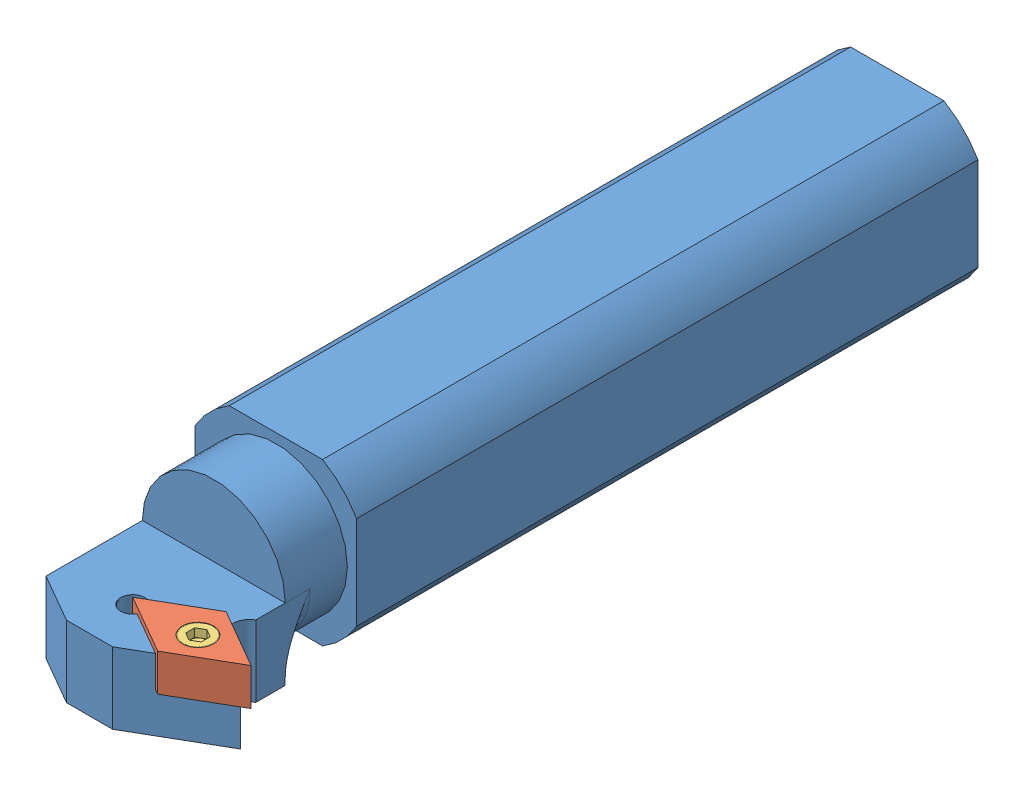
SolidWorks assembly 镗刀, configuration 默认. Lengths in mm.
Overall size (31.47 25.98 130).
3 component instances, 3 part files, 5 mates.
Components (placement in the parent):
- 镗刀刀柄-1: 镗刀刀柄 [默认] at (-3.2581 2.8626 -65) size (29.74 25.98 130)
- 镗刀刀片-2: 镗刀刀片 [默认] at (5.6946 -2.1374 57.4707) x (1 0 0) z (0 1 0) size (19.05 11 6)
- hexagon socket head cap screws gb-1: hexagon socket head cap screws gb [GB_FASTENER_SCREWS_HSHCS M3X5-N] at (6.6683 3.8626 57.4707) x (0 -1 0) z (0 0 1) size (8 5.5 5.5)
Mates (geometry in assembly coordinates):
- 重合4: coincident anti-aligned: plane of 镗刀刀柄-1 through (-3.8317 -2.1374 57.4707) normal (0 1 0); plane of 镗刀刀片-2 through (5.6946 -2.1374 57.4707) normal (0 -1 0)
- 重合5: coincident anti-aligned: plane of 镗刀刀柄-1 through (4.8286 -2.1374 62.4707) normal (0.5 0 -0.866025); plane of 镗刀刀片-2 through (-3.8317 3.8626 57.4707) normal (-0.5 0 0.866025)
- 重合6: coincident anti-aligned: plane of 镗刀刀柄-1 through (-2.156 -2.1374 56.5033) normal (0.5 0 0.866025); plane of 镗刀刀片-2 through (5.6946 3.8626 51.9707) normal (-0.5 0 -0.866025)
- 同心1: concentric aligned: cylinder of 镗刀刀片-2 through (6.6683 3.8626 57.4707) axis (0 1 0) radius 2.5; cylinder of hexagon socket head cap screws gb-1 through (6.6683 -4.1374 57.4707) axis (0 1 0) radius 1.5
- 重合7: coincident anti-aligned: plane of 镗刀刀片-2 through (8.1683 0.8626 57.4707) normal (0 1 0); plane of hexagon socket head cap screws gb-1 through (6.6683 0.8626 57.4707) normal (0 -1 0)
